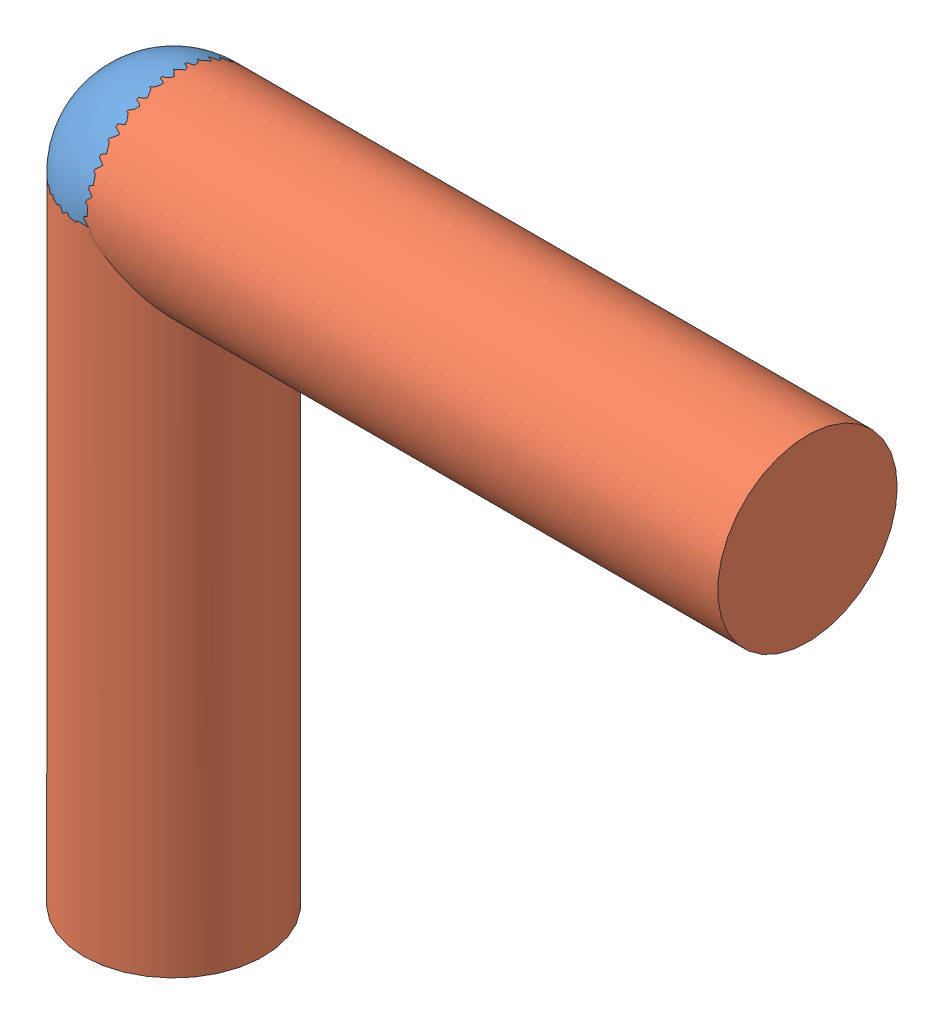
SolidWorks assembly Assem2, configuration Varsayılan. Lengths in mm.
Overall size (13.3 13.3 3.3).
3 component instances, 2 part files, 2 mates.
Components (placement in the parent):
- Part1-1: Part1 [Varsayılan] at (2.5366 1.1422 3.3) size (3.3 3.3 3.3)
- Part2-1: Part2 [Varsayılan] at (2.5366 1.1422 3.3) size (11.65 3.3 3.3)
- Part2-2: Part2 [Varsayılan] at (2.5366 1.1422 3.3) x (0 -1 0) z (0 0 -1) size (11.65 3.3 3.3)
Mates (geometry in assembly coordinates):
- Concentric1: concentric: sphere of Part1-1; sphere of Part2-1
- Concentric2: concentric: sphere of Part1-1; sphere of Part2-2
